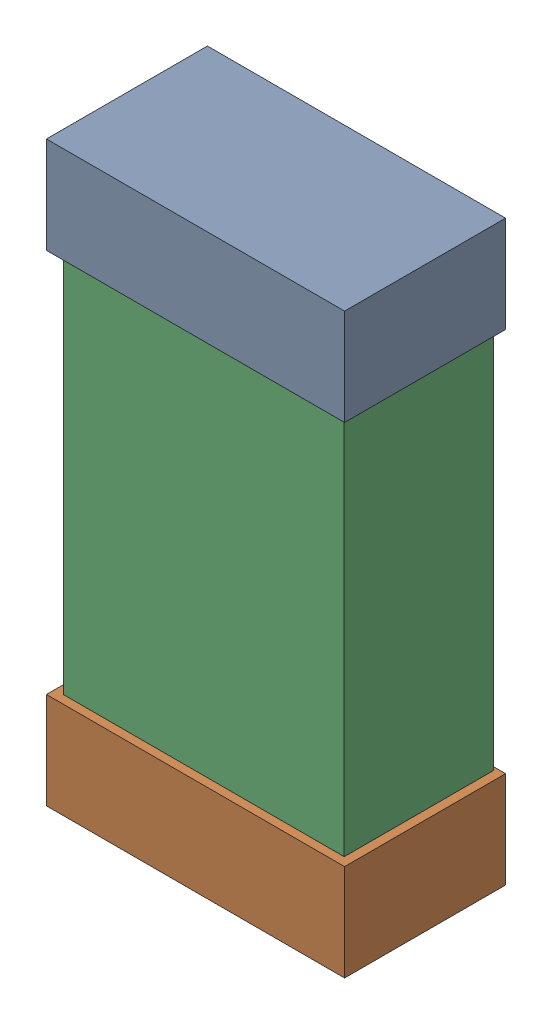
SolidWorks assembly R26, configuration Default. Lengths in mm.
Overall size (0.85 1.65 0.46).
6 component instances, 2 part files, 0 mates.
Components (placement in the parent):
- 432138512_112-1: 432138512_112 [Default] at (15.7551 20.139 -0.8715) size (0.85 0.28 0.46)
  - Extruded-1: Extruded [Default] at origin size (0.85 0.28 0.46)
- 432138512_113-1: 432138512_113 [Default] at (15.7551 18.7675 -0.8715) size (0.85 0.28 0.46)
  - Extruded-1: Extruded [Default] at origin size (0.85 0.28 0.46)
- 432124816_56-1: 432124816_56 [Default] at (15.7551 19.4533 -0.8615) size (0.8 1.5 0.42)
  - Extruded (1)-1: Extruded (1) [Default] at origin size (0.8 1.5 0.42)
